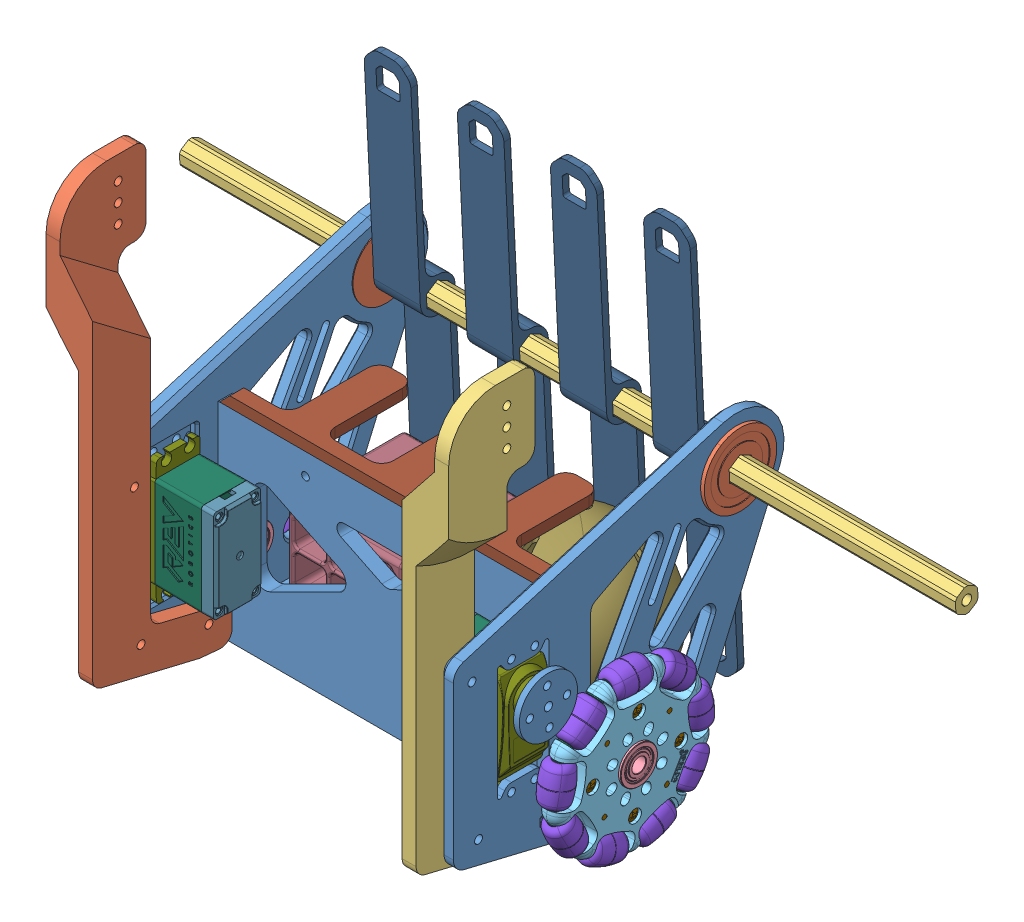
SolidWorks assembly Intake2, configuration Default. Lengths in mm.
Overall size (333.38 212.44 158.53).
109 component instances, 21 part files, 66 mates.
Components (placement in the parent):
- IntakeWide-1: IntakeWide [Default] at (-43.2378 29.5162 123.384) size (157 122.29 142.09)
- 0_375_Hex_ID_x_1_125_OD_x_0_313_WD_Flanged_Bearing_217-2735 (1).step-1: 0_375_Hex_ID_x_1_125_OD_x_0_313_WD_Flanged_Bearing_217-2735 (1).step [Default] at (101.4122 125.5162 108.384) x (0 0.54174 -0.840546) z (0 -0.840546 -0.54174) size (31.12 7.94 31.12)
- 0_375_Hex_ID_x_1_125_OD_x_0_313_WD_Flanged_Bearing_217-2735 (1).step-2: 0_375_Hex_ID_x_1_125_OD_x_0_313_WD_Flanged_Bearing_217-2735 (1).step [Default] at (-42.8878 125.5162 108.384) x (0 0.998804 0.048888) z (0 -0.048888 0.998804) size (31.12 7.94 31.12)
- 375Hex13.3in-1: 375Hex13.3in [Default] at (-250.6814 125.5123 108.3763) x (0 0.54174 -0.840546) z (-1 0 0) size (10.24 9.53 333.38)
- 1601-0014-0006.step-1: 1601-0014-0006.step [Default] at (105.8122 50.5162 165.184) x (0 -0.381849 0.924225) z (0 -0.924225 -0.381849) size (15.95 5 15.95)
- 1601-0014-0006.step-2: 1601-0014-0006.step [Default] at (-47.2878 50.5162 165.184) x (0 -1 0) z (0 0 1) size (15.95 5 15.95)
- 3604-0014-0072 assembly.STEP-1: 3604-0014-0072 assembly.STEP [Default] at (98.0385 34.1974 194.2388) x (0 -0.339821 0.94049) z (0 0.94049 0.339821) size (78.59 16.98 77.39)
  - 3604-0014-0072 wheel half.STEP-1: 3604-0014-0072 wheel half.STEP [Default] at (-32.8712 13.6737 5.4742) size (67.84 5 66.97)
  - 3604-0014-0072 wheel half.STEP-2: 3604-0014-0072 wheel half.STEP [Default] at (-32.8712 23.6737 5.4742) x (-1 0 0) z (0 0 1) size (67.84 5 66.97)
  - 3604-0014-0072 bushing.STEP-1: 3604-0014-0072 bushing.STEP [Default] at (-52.1548 18.6737 -17.5071) x (-0.130318 0.979233 -0.155307) z (-0.766044 0 0.642788) size (5.61 5.61 17.1)
  - 3604-0014-0072 shaft.STEP-1: 3604-0014-0072 shaft.STEP [Default] at (-60.0068 18.6737 -10.9185) x (0.629069 0.205497 0.749695) z (-0.132091 0.978658 -0.15742) size (3.17 20.5 3.17)
  - 3604-0014-0072 roller.STEP-1: 3604-0014-0072 roller.STEP [Default] at (-52.1548 18.6737 -17.5071) x (-0.385664 0.800009 -0.459617) z (-0.766044 0 0.642788) size (12.13 12.13 16)
  - 3604-0014-0072 shaft.STEP-2: 3604-0014-0072 shaft.STEP [Default] at (-43.1212 18.6737 -24.5258) x (0 0.205497 0.978658) z (0 0.978658 -0.205497) size (3.17 20.5 3.17)
  - 3604-0014-0072 shaft.STEP-3: 3604-0014-0072 shaft.STEP [Default] at (-21.4395 18.6737 -24.0957) x (-0.629069 0.205497 0.749695) z (0.132091 0.978658 -0.15742) size (3.17 20.5 3.17)
  - 3604-0014-0072 shaft.STEP-4: 3604-0014-0072 shaft.STEP [Default] at (-5.1069 18.6737 -9.8295) x (-0.96379 0.205497 0.169942) z (0.202375 0.978658 -0.035684) size (3.17 20.5 3.17)
  - 3604-0014-0072 shaft.STEP-5: 3604-0014-0072 shaft.STEP [Default] at (-1.7654 18.6737 11.5975) x (-0.847543 0.205497 -0.489329) z (0.177965 0.978658 0.102748) size (3.17 20.5 3.17)
  - 3604-0014-0072 shaft.STEP-6: 3604-0014-0072 shaft.STEP [Default] at (-12.9787 18.6737 30.1593) x (-0.334721 0.205497 -0.919638) z (0.070284 0.978658 0.193104) size (3.17 20.5 3.17)
  - 3604-0014-0072 shaft.STEP-7: 3604-0014-0072 shaft.STEP [Default] at (-33.4999 18.6737 37.1707) x (0.334721 0.205497 -0.919638) z (-0.070284 0.978658 0.193104) size (3.17 20.5 3.17)
  - 3604-0014-0072 shaft.STEP-8: 3604-0014-0072 shaft.STEP [Default] at (-53.727 18.6737 29.351) x (0.847543 0.205497 -0.489329) z (-0.177965 0.978658 0.102748) size (3.17 20.5 3.17)
  - 3604-0014-0072 shaft.STEP-9: 3604-0014-0072 shaft.STEP [Default] at (-64.1953 18.6737 10.3591) x (0.96379 0.205497 0.169942) z (-0.202375 0.978658 -0.035684) size (3.17 20.5 3.17)
  - 3604-0014-0072 bushing.STEP-2: 3604-0014-0072 bushing.STEP [Default] at (-32.8712 18.6737 -24.5258) x (0 0.979233 -0.202739) z (-1 0 0) size (5.61 5.61 17.1)
  - 3604-0014-0072 bushing.STEP-3: 3604-0014-0072 bushing.STEP [Default] at (-13.5876 18.6737 -17.5071) x (0.130318 0.979233 -0.155307) z (-0.766044 0 -0.642788) size (5.61 5.61 17.1)
  - 3604-0014-0072 bushing.STEP-4: 3604-0014-0072 bushing.STEP [Default] at (-3.327 18.6737 0.2648) x (0.199659 0.979233 -0.035205) z (-0.173648 0 -0.984808) size (5.61 5.61 17.1)
  - 3604-0014-0072 bushing.STEP-5: 3604-0014-0072 bushing.STEP [Default] at (-6.8904 18.6737 20.4742) x (0.175577 0.979233 0.101369) z (0.5 0 -0.866025) size (5.61 5.61 17.1)
  - 3604-0014-0072 bushing.STEP-6: 3604-0014-0072 bushing.STEP [Default] at (-22.6106 18.6737 33.665) x (0.069341 0.979233 0.190512) z (0.939693 0 -0.34202) size (5.61 5.61 17.1)
  - 3604-0014-0072 bushing.STEP-7: 3604-0014-0072 bushing.STEP [Default] at (-43.1318 18.6737 33.665) x (-0.069341 0.979233 0.190512) z (0.939693 0 0.34202) size (5.61 5.61 17.1)
  - 3604-0014-0072 bushing.STEP-8: 3604-0014-0072 bushing.STEP [Default] at (-58.852 18.6737 20.4742) x (-0.175577 0.979233 0.101369) z (0.5 0 0.866025) size (5.61 5.61 17.1)
  - 3604-0014-0072 bushing.STEP-9: 3604-0014-0072 bushing.STEP [Default] at (-62.4154 18.6737 0.2648) x (-0.199659 0.979233 -0.035205) z (-0.173648 0 0.984808) size (5.61 5.61 17.1)
  - 3604-0014-0072 roller.STEP-2: 3604-0014-0072 roller.STEP [Default] at (-32.8712 18.6737 -24.5258) x (0 0.800009 -0.599987) z (-1 0 0) size (12.13 12.13 16)
  - 3604-0014-0072 roller.STEP-3: 3604-0014-0072 roller.STEP [Default] at (-13.5876 18.6737 -17.5071) x (0.385664 0.800009 -0.459617) z (-0.766044 0 -0.642788) size (12.13 12.13 16)
  - 3604-0014-0072 roller.STEP-4: 3604-0014-0072 roller.STEP [Default] at (-3.327 18.6737 0.2648) x (0.590872 0.800009 -0.104187) z (-0.173648 0 -0.984808) size (12.13 12.13 16)
  - 3604-0014-0072 roller.STEP-5: 3604-0014-0072 roller.STEP [Default] at (-6.8904 18.6737 20.4742) x (0.519604 0.800009 0.299994) z (0.5 0 -0.866025) size (12.13 12.13 16)
  - 3604-0014-0072 roller.STEP-6: 3604-0014-0072 roller.STEP [Default] at (-22.6106 18.6737 33.665) x (0.205208 0.800009 0.563804) z (0.939693 0 -0.34202) size (12.13 12.13 16)
  - 3604-0014-0072 roller.STEP-7: 3604-0014-0072 roller.STEP [Default] at (-43.1318 18.6737 33.665) x (-0.205208 0.800009 0.563804) z (0.939693 0 0.34202) size (12.13 12.13 16)
  - 3604-0014-0072 roller.STEP-8: 3604-0014-0072 roller.STEP [Default] at (-58.852 18.6737 20.4742) x (-0.519604 0.800009 0.299994) z (0.5 0 0.866025) size (12.13 12.13 16)
  - 3604-0014-0072 roller.STEP-9: 3604-0014-0072 roller.STEP [Default] at (-62.4154 18.6737 0.2648) x (-0.590872 0.800009 -0.104187) z (-0.173648 0 0.984808) size (12.13 12.13 16)
  - 364 omni wheel screw_99461A110.STEP-1: 364 omni wheel screw_99461A110.STEP [Default] at (-40.1422 17.6737 23.0279) x (1 0 0) z (0 1 0) size (5.22 5.22 9.61)
  - 364 omni wheel screw_99461A110.STEP-2: 364 omni wheel screw_99461A110.STEP [Default] at (-50.4249 17.6737 -1.7968) x (0 0 1) z (0 1 0) size (5.22 5.22 9.61)
  - 364 omni wheel screw_99461A110.STEP-3: 364 omni wheel screw_99461A110.STEP [Default] at (-25.6002 17.6737 -12.0795) x (-1 0 0) z (0 1 0) size (5.22 5.22 9.61)
  - 364 omni wheel screw_99461A110.STEP-4: 364 omni wheel screw_99461A110.STEP [Default] at (-15.3175 17.6737 12.7452) x (0 0 -1) z (0 1 0) size (5.22 5.22 9.61)
  - 364 omni wheel screw_99461A110.STEP-5: 364 omni wheel screw_99461A110.STEP [Default] at (-25.6002 19.6737 23.0279) x (-0.837169 0 -0.546944) z (0 -1 0) size (5.22 5.22 9.61)
  - 364 omni wheel screw_99461A110.STEP-6: 364 omni wheel screw_99461A110.STEP [Default] at (-15.3175 19.6737 -1.7968) x (-0.546944 0 0.837169) z (0 -1 0) size (5.22 5.22 9.61)
  - 364 omni wheel screw_99461A110.STEP-7: 364 omni wheel screw_99461A110.STEP [Default] at (-40.1422 19.6737 -12.0795) x (0.837169 0 0.546944) z (0 -1 0) size (5.22 5.22 9.61)
  - 364 omni wheel screw_99461A110.STEP-8: 364 omni wheel screw_99461A110.STEP [Default] at (-50.4249 19.6737 12.7452) x (0.546944 0 -0.837169) z (0 -1 0) size (5.22 5.22 9.61)
- 1601-0014-0006.step-5: 1601-0014-0006.step [Default] at (117.6622 50.5162 165.184) x (0 0.825172 0.564882) z (0 0.564882 -0.825172) size (15.95 5 15.95)
- 1601-0014-0006.step-6: 1601-0014-0006.step [Default] at (115.7622 50.5162 165.184) x (0 -0.381849 0.924225) z (0 -0.924225 -0.381849) size (15.95 5 15.95)
- 1601-0014-0006.step-7: 1601-0014-0006.step [Default] at (-58.1878 50.5162 165.184) x (0 -0.381849 0.924225) z (0 -0.924225 -0.381849) size (15.95 5 15.95)
- 1601-0014-0006.step-8: 1601-0014-0006.step [Default] at (-56.2878 50.5162 165.184) x (0 0.825172 0.564882) z (0 0.564882 -0.825172) size (15.95 5 15.95)
- 3604-0014-0072 assembly.STEP-2: 3604-0014-0072 assembly.STEP [Default] at (-75.9115 34.6322 194.4787) x (0 -0.32577 0.945449) z (0 0.945449 0.32577) size (78.59 16.98 77.39)
  - 3604-0014-0072 wheel half.STEP-1: 3604-0014-0072 wheel half.STEP [Default] at (-32.8712 13.6737 5.4742) size (67.84 5 66.97)
  - 3604-0014-0072 wheel half.STEP-2: 3604-0014-0072 wheel half.STEP [Default] at (-32.8712 23.6737 5.4742) x (-1 0 0) z (0 0 1) size (67.84 5 66.97)
  - 3604-0014-0072 bushing.STEP-1: 3604-0014-0072 bushing.STEP [Default] at (-52.1548 18.6737 -17.5071) x (-0.130318 0.979233 -0.155307) z (-0.766044 0 0.642788) size (5.61 5.61 17.1)
  - 3604-0014-0072 shaft.STEP-1: 3604-0014-0072 shaft.STEP [Default] at (-60.0068 18.6737 -10.9185) x (0.629069 0.205497 0.749695) z (-0.132091 0.978658 -0.15742) size (3.17 20.5 3.17)
  - 3604-0014-0072 roller.STEP-1: 3604-0014-0072 roller.STEP [Default] at (-52.1548 18.6737 -17.5071) x (-0.385664 0.800009 -0.459617) z (-0.766044 0 0.642788) size (12.13 12.13 16)
  - 3604-0014-0072 shaft.STEP-2: 3604-0014-0072 shaft.STEP [Default] at (-43.1212 18.6737 -24.5258) x (0 0.205497 0.978658) z (0 0.978658 -0.205497) size (3.17 20.5 3.17)
  - 3604-0014-0072 shaft.STEP-3: 3604-0014-0072 shaft.STEP [Default] at (-21.4395 18.6737 -24.0957) x (-0.629069 0.205497 0.749695) z (0.132091 0.978658 -0.15742) size (3.17 20.5 3.17)
  - 3604-0014-0072 shaft.STEP-4: 3604-0014-0072 shaft.STEP [Default] at (-5.1069 18.6737 -9.8295) x (-0.96379 0.205497 0.169942) z (0.202375 0.978658 -0.035684) size (3.17 20.5 3.17)
  - 3604-0014-0072 shaft.STEP-5: 3604-0014-0072 shaft.STEP [Default] at (-1.7654 18.6737 11.5975) x (-0.847543 0.205497 -0.489329) z (0.177965 0.978658 0.102748) size (3.17 20.5 3.17)
  - 3604-0014-0072 shaft.STEP-6: 3604-0014-0072 shaft.STEP [Default] at (-12.9787 18.6737 30.1593) x (-0.334721 0.205497 -0.919638) z (0.070284 0.978658 0.193104) size (3.17 20.5 3.17)
  - 3604-0014-0072 shaft.STEP-7: 3604-0014-0072 shaft.STEP [Default] at (-33.4999 18.6737 37.1707) x (0.334721 0.205497 -0.919638) z (-0.070284 0.978658 0.193104) size (3.17 20.5 3.17)
  - 3604-0014-0072 shaft.STEP-8: 3604-0014-0072 shaft.STEP [Default] at (-53.727 18.6737 29.351) x (0.847543 0.205497 -0.489329) z (-0.177965 0.978658 0.102748) size (3.17 20.5 3.17)
  - 3604-0014-0072 shaft.STEP-9: 3604-0014-0072 shaft.STEP [Default] at (-64.1953 18.6737 10.3591) x (0.96379 0.205497 0.169942) z (-0.202375 0.978658 -0.035684) size (3.17 20.5 3.17)
  - 3604-0014-0072 bushing.STEP-2: 3604-0014-0072 bushing.STEP [Default] at (-32.8712 18.6737 -24.5258) x (0 0.979233 -0.202739) z (-1 0 0) size (5.61 5.61 17.1)
  - 3604-0014-0072 bushing.STEP-3: 3604-0014-0072 bushing.STEP [Default] at (-13.5876 18.6737 -17.5071) x (0.130318 0.979233 -0.155307) z (-0.766044 0 -0.642788) size (5.61 5.61 17.1)
  - 3604-0014-0072 bushing.STEP-4: 3604-0014-0072 bushing.STEP [Default] at (-3.327 18.6737 0.2648) x (0.199659 0.979233 -0.035205) z (-0.173648 0 -0.984808) size (5.61 5.61 17.1)
  - 3604-0014-0072 bushing.STEP-5: 3604-0014-0072 bushing.STEP [Default] at (-6.8904 18.6737 20.4742) x (0.175577 0.979233 0.101369) z (0.5 0 -0.866025) size (5.61 5.61 17.1)
  - 3604-0014-0072 bushing.STEP-6: 3604-0014-0072 bushing.STEP [Default] at (-22.6106 18.6737 33.665) x (0.069341 0.979233 0.190512) z (0.939693 0 -0.34202) size (5.61 5.61 17.1)
  - 3604-0014-0072 bushing.STEP-7: 3604-0014-0072 bushing.STEP [Default] at (-43.1318 18.6737 33.665) x (-0.069341 0.979233 0.190512) z (0.939693 0 0.34202) size (5.61 5.61 17.1)
  - 3604-0014-0072 bushing.STEP-8: 3604-0014-0072 bushing.STEP [Default] at (-58.852 18.6737 20.4742) x (-0.175577 0.979233 0.101369) z (0.5 0 0.866025) size (5.61 5.61 17.1)
  - 3604-0014-0072 bushing.STEP-9: 3604-0014-0072 bushing.STEP [Default] at (-62.4154 18.6737 0.2648) x (-0.199659 0.979233 -0.035205) z (-0.173648 0 0.984808) size (5.61 5.61 17.1)
  - 3604-0014-0072 roller.STEP-2: 3604-0014-0072 roller.STEP [Default] at (-32.8712 18.6737 -24.5258) x (0 0.800009 -0.599987) z (-1 0 0) size (12.13 12.13 16)
  - 3604-0014-0072 roller.STEP-3: 3604-0014-0072 roller.STEP [Default] at (-13.5876 18.6737 -17.5071) x (0.385664 0.800009 -0.459617) z (-0.766044 0 -0.642788) size (12.13 12.13 16)
  - 3604-0014-0072 roller.STEP-4: 3604-0014-0072 roller.STEP [Default] at (-3.327 18.6737 0.2648) x (0.590872 0.800009 -0.104187) z (-0.173648 0 -0.984808) size (12.13 12.13 16)
  - 3604-0014-0072 roller.STEP-5: 3604-0014-0072 roller.STEP [Default] at (-6.8904 18.6737 20.4742) x (0.519604 0.800009 0.299994) z (0.5 0 -0.866025) size (12.13 12.13 16)
  - 3604-0014-0072 roller.STEP-6: 3604-0014-0072 roller.STEP [Default] at (-22.6106 18.6737 33.665) x (0.205208 0.800009 0.563804) z (0.939693 0 -0.34202) size (12.13 12.13 16)
  - 3604-0014-0072 roller.STEP-7: 3604-0014-0072 roller.STEP [Default] at (-43.1318 18.6737 33.665) x (-0.205208 0.800009 0.563804) z (0.939693 0 0.34202) size (12.13 12.13 16)
  - 3604-0014-0072 roller.STEP-8: 3604-0014-0072 roller.STEP [Default] at (-58.852 18.6737 20.4742) x (-0.519604 0.800009 0.299994) z (0.5 0 0.866025) size (12.13 12.13 16)
  - 3604-0014-0072 roller.STEP-9: 3604-0014-0072 roller.STEP [Default] at (-62.4154 18.6737 0.2648) x (-0.590872 0.800009 -0.104187) z (-0.173648 0 0.984808) size (12.13 12.13 16)
  - 364 omni wheel screw_99461A110.STEP-1: 364 omni wheel screw_99461A110.STEP [Default] at (-40.1422 17.6737 23.0279) x (1 0 0) z (0 1 0) size (5.22 5.22 9.61)
  - 364 omni wheel screw_99461A110.STEP-2: 364 omni wheel screw_99461A110.STEP [Default] at (-50.4249 17.6737 -1.7968) x (0 0 1) z (0 1 0) size (5.22 5.22 9.61)
  - 364 omni wheel screw_99461A110.STEP-3: 364 omni wheel screw_99461A110.STEP [Default] at (-25.6002 17.6737 -12.0795) x (-1 0 0) z (0 1 0) size (5.22 5.22 9.61)
  - 364 omni wheel screw_99461A110.STEP-4: 364 omni wheel screw_99461A110.STEP [Default] at (-15.3175 17.6737 12.7452) x (0 0 -1) z (0 1 0) size (5.22 5.22 9.61)
  - 364 omni wheel screw_99461A110.STEP-5: 364 omni wheel screw_99461A110.STEP [Default] at (-25.6002 19.6737 23.0279) x (-0.837169 0 -0.546944) z (0 -1 0) size (5.22 5.22 9.61)
  - 364 omni wheel screw_99461A110.STEP-6: 364 omni wheel screw_99461A110.STEP [Default] at (-15.3175 19.6737 -1.7968) x (-0.546944 0 0.837169) z (0 -1 0) size (5.22 5.22 9.61)
  - 364 omni wheel screw_99461A110.STEP-7: 364 omni wheel screw_99461A110.STEP [Default] at (-40.1422 19.6737 -12.0795) x (0.837169 0 0.546944) z (0 -1 0) size (5.22 5.22 9.61)
  - 364 omni wheel screw_99461A110.STEP-8: 364 omni wheel screw_99461A110.STEP [Default] at (-50.4249 19.6737 12.7452) x (0.546944 0 -0.837169) z (0 -1 0) size (5.22 5.22 9.61)
- IntakeFlap-1: IntakeFlap [Default] at (99.2622 125.5123 108.3763) x (0 -0.998804 -0.048888) z (-1 0 0) size (180 15 20)
- IntakeFlap-2: IntakeFlap [Default] at (59.2622 125.5123 108.3763) x (0 -0.998804 -0.048888) z (-1 0 0) size (180 15 20)
- IntakeFlap-3: IntakeFlap [Default] at (19.2622 125.5123 108.3763) x (0 -0.998804 -0.048888) z (-1 0 0) size (180 15 20)
- IntakeFlap-4: IntakeFlap [Default] at (-20.7378 125.5123 108.3763) x (0 -0.998804 -0.048888) z (-1 0 0) size (180 15 20)
- Part10^Intake2-1: Part10^Intake2 [Default] at (-43.2378 110.5162 123.384) x (1 0 0) z (0 1 0) size (144 45 18.5) (virtual)
- am-2850 wiffle base Ball.step-1: am-2850 wiffle base Ball.step [Default] at (66.2022 65.0762 138.624) x (0.76558 0.27445 0.581863) z (-0.623857 0.095806 0.775644) size (71.12 71.12 71.12)
- ftc-2013 2in Cube.step-1: ftc-2013 2in Cube.step [Default] at (2.2547 54.9162 145.784) size (50.8 50.8 50.94)
- REV-41-1097.STEP-1: REV-41-1097.STEP [Default] at (-13.8878 77.7662 200.1841) x (0 0 1) z (1 0 0) size (24.05 54 43.73)
  - A.STEP-1: A.STEP [Default] at origin size (20.15 40.13 8.54)
  - E.STEP-1: E.STEP [Default] at origin size (20.15 40.15 20.1)
  - C.STEP-1: C.STEP [Default] at origin size (24.05 54 13.28)
  - B.STEP-1: B.STEP [Default] at origin size (9 9 4.4)
  - D.STEP-1: D.STEP [Default] at (0 -10.0526 -30.1) x (-1 0 0) z (0 0 1) size (17.21 17.2 14.7)
- REV-41-1097.STEP-2: REV-41-1097.STEP [Default] at (72.4122 77.7662 200.1835) x (0 0 -1) z (-1 0 0) size (24.05 54 43.73)
  - A.STEP-1: A.STEP [Default] at origin size (20.15 40.13 8.54)
  - E.STEP-1: E.STEP [Default] at origin size (20.15 40.15 20.1)
  - C.STEP-1: C.STEP [Default] at origin size (24.05 54 13.28)
  - B.STEP-1: B.STEP [Default] at origin size (9 9 4.4)
  - D.STEP-1: D.STEP [Default] at (0 -10.0526 -30.1) x (-1 0 0) z (0 0 1) size (17.21 17.2 14.7)
- IntakeServoHorn-1: IntakeServoHorn [Default] at (-55.5878 87.8188 200.1841) x (0 0.715777 -0.698329) z (0 0.698329 0.715777) size (25 6 25)
- IntakeServoHorn-2: IntakeServoHorn [Default] at (114.1122 87.8188 200.1835) x (0 0.059406 -0.998234) z (0 -0.998234 -0.059406) size (25 6 25)
- Part2^Intake2-1: Part2^Intake2 [Default] at (-43.2378 29.5162 123.384) x (0 0 -1) z (1 0 0) size (60 191.86 20) (virtual)
- IntakeArm2Mir-1: IntakeArm2Mir [Default] at (89.7622 29.5162 123.384) x (0 0 -1) z (1 0 0) size (60 191.86 20)
Mates (geometry in assembly coordinates):
- Concentric1: concentric: cylinder of IntakeWide-1 through (101.7622 125.5162 108.384) axis (1 0 0) radius 14.2875; cylinder of 0_375_Hex_ID_x_1_125_OD_x_0_313_WD_Flanged_Bearing_217-2735 (1).step-1 through (101.4122 125.5162 108.384) axis (1 0 0) radius 14.2748
- Coincident1: coincident: plane of IntakeWide-1 through (107.7622 23.5162 174.184) normal (1 0 0); plane of 0_375_Hex_ID_x_1_125_OD_x_0_313_WD_Flanged_Bearing_217-2735 (1).step-1 through (107.7622 133.9444 95.3072) normal (-1 0 0)
- Concentric2: concentric: cylinder of IntakeWide-1 through (-43.2378 125.5162 108.384) axis (-1 0 0) radius 14.2875; cylinder of 0_375_Hex_ID_x_1_125_OD_x_0_313_WD_Flanged_Bearing_217-2735 (1).step-2 through (-42.8878 125.5162 108.384) axis (-1 0 0) radius 14.2748
- Coincident2: coincident: plane of IntakeWide-1 through (-49.2378 23.5162 174.184) normal (-1 0 0); plane of 0_375_Hex_ID_x_1_125_OD_x_0_313_WD_Flanged_Bearing_217-2735 (1).step-2 through (-49.2378 141.0551 109.1446) normal (1 0 0)
- Coincident3: coincident: plane of 0_375_Hex_ID_x_1_125_OD_x_0_313_WD_Flanged_Bearing_217-2735 (1).step-1 through (127.3102 122.9988 103.4851) normal (0 0.840546 0.54174); plane of 375Hex13.3in-1 through (-707.8814 122.9988 103.4851) normal (0 -0.840546 -0.54174)
- Coincident4: coincident: plane of 0_375_Hex_ID_x_1_125_OD_x_0_313_WD_Flanged_Bearing_217-2735 (1).step-2 through (-68.7858 120.0149 108.1147) normal (0 0.840546 0.54174); plane of 375Hex13.3in-1 through (-707.8814 122.9988 103.4851) normal (0 -0.840546 -0.54174)
- Coincident5: coincident: plane of 0_375_Hex_ID_x_1_125_OD_x_0_313_WD_Flanged_Bearing_217-2735 (1).step-1 through (127.3102 128.5001 103.7544) normal (0 -0.048888 0.998804); plane of 375Hex13.3in-1 through (-707.8814 128.4914 103.7539) normal (0 0.048888 -0.998804)
- Concentric3: concentric: cylinder of IntakeWide-1 through (-49.2378 50.5162 165.184) axis (1 0 0) radius 7.05; cylinder of 1601-0014-0006.step-1 through (101.7622 50.5162 165.184) axis (1 0 0) radius 7
- Coincident6: coincident: plane of IntakeWide-1 through (101.7622 29.5162 174.184) normal (-1 0 0); plane of 1601-0014-0006.step-1 through (101.7622 50.5162 165.184) normal (1 0 0)
- Coincident7: coincident: plane of IntakeWide-1 through (-43.2378 29.5162 174.184) normal (1 0 0); plane of 1601-0014-0006.step-2 through (-43.2378 50.5162 165.184) normal (-1 0 0)
- Concentric4: concentric: cylinder of IntakeWide-1 through (-49.2378 50.5162 165.184) axis (1 0 0) radius 7.05; cylinder of 1601-0014-0006.step-2 through (-43.2378 50.5162 165.184) axis (-1 0 0) radius 7
- Coincident8: coincident: circle of 3604-0014-0072 assembly.STEP-1/3604-0014-0072 wheel half.STEP-2; cylinder of 1601-0014-0006.step-5 through (121.7122 50.5162 165.184) axis (-1 0 0) radius 7
- Coincident9: coincident: plane of 3604-0014-0072 assembly.STEP-1/3604-0014-0072 wheel half.STEP-2 through (121.7122 50.5162 165.184) normal (1 0 0); plane of 1601-0014-0006.step-5 through (121.7122 50.5162 165.184) normal (-1 0 0)
- Concentric5: concentric: cylinder of 3604-0014-0072 assembly.STEP-1/3604-0014-0072 wheel half.STEP-1 through (111.7122 50.5162 165.184) axis (1 0 0) radius 7; cylinder of 1601-0014-0006.step-6 through (111.7122 50.5162 165.184) axis (1 0 0) radius 7
- Coincident10: coincident: plane of 3604-0014-0072 assembly.STEP-1/3604-0014-0072 wheel half.STEP-1 through (111.7122 50.5162 165.184) normal (-1 0 0); plane of 1601-0014-0006.step-6 through (111.7122 50.5162 165.184) normal (1 0 0)
- Concentric6: concentric: cylinder of 1601-0014-0006.step-1 through (105.8122 50.5162 165.184) axis (-1 0 0) radius 3; cylinder of 1601-0014-0006.step-5 through (117.6622 50.5162 165.184) axis (1 0 0) radius 3
- Distance2: distance = 3 mm: plane of 1601-0014-0006.step-6 through (110.7622 50.5162 165.184) normal (-1 0 0); plane of IntakeWide-1 through (107.7622 23.5162 174.184) normal (1 0 0)
- Concentric7: concentric: cylinder of 1601-0014-0006.step-7 through (-62.2378 50.5162 165.184) axis (1 0 0) radius 7; cylinder of 3604-0014-0072 assembly.STEP-2/3604-0014-0072 wheel half.STEP-1 through (-62.2378 50.5162 165.184) axis (1 0 0) radius 7
- Coincident13: coincident: cylinder of 1601-0014-0006.step-8 through (-52.2378 50.5162 165.184) axis (-1 0 0) radius 7; circle of 3604-0014-0072 assembly.STEP-2/3604-0014-0072 wheel half.STEP-2
- Coincident14: coincident: plane of 1601-0014-0006.step-8 through (-52.2378 50.5162 165.184) normal (-1 0 0); plane of 3604-0014-0072 assembly.STEP-2/3604-0014-0072 wheel half.STEP-2 through (-52.2378 50.5162 165.184) normal (1 0 0)
- Coincident15: coincident: plane of 1601-0014-0006.step-7 through (-62.2378 50.5162 165.184) normal (1 0 0); plane of 3604-0014-0072 assembly.STEP-2/3604-0014-0072 wheel half.STEP-1 through (-62.2378 50.5162 165.184) normal (-1 0 0)
- Concentric8: concentric: cylinder of 1601-0014-0006.step-2 through (-47.2878 50.5162 165.184) axis (1 0 0) radius 3; cylinder of 1601-0014-0006.step-7 through (-58.1878 50.5162 165.184) axis (-1 0 0) radius 3
- Distance3: distance = 3 mm: plane of 3604-0014-0072 assembly.STEP-2/3604-0014-0072 wheel half.STEP-2 through (-52.2378 50.5162 165.184) normal (1 0 0); plane of IntakeWide-1 through (-49.2378 23.5162 174.184) normal (-1 0 0)
- Coincident17: coincident: plane of 375Hex13.3in-1 through (-707.8814 128.4914 103.7539) normal (0 0.048888 -0.998804); plane of IntakeFlap-1 through (79.2622 128.4914 103.7539) normal (0 -0.048888 0.998804)
- Coincident18: coincident: plane of 375Hex13.3in-1 through (-707.8814 122.9988 103.4851) normal (0 -0.840546 -0.54174); plane of IntakeFlap-1 through (79.2622 122.9988 103.4851) normal (0 0.840546 0.54174)
- Coincident19: coincident: plane of 375Hex13.3in-1 through (-707.8814 122.5331 112.9987) normal (0 -0.048888 0.998804); plane of IntakeFlap-2 through (39.2622 122.5331 112.9987) normal (0 0.048888 -0.998804)
- Coincident20: coincident: plane of 375Hex13.3in-1 through (-707.8814 122.5331 112.9987) normal (0 -0.048888 0.998804); plane of IntakeFlap-3 through (-0.7378 122.5331 112.9987) normal (0 0.048888 -0.998804)
- Coincident21: coincident: plane of 375Hex13.3in-1 through (-707.8814 122.5331 112.9987) normal (0 -0.048888 0.998804); plane of IntakeFlap-4 through (-40.7378 122.5331 112.9987) normal (0 0.048888 -0.998804)
- Coincident22: coincident: plane of 375Hex13.3in-1 through (-707.8814 128.0258 113.2675) normal (0 0.840546 0.54174); plane of IntakeFlap-2 through (39.2622 128.0258 113.2675) normal (0 -0.840546 -0.54174)
- Coincident23: coincident: plane of 375Hex13.3in-1 through (-707.8814 128.0258 113.2675) normal (0 0.840546 0.54174); plane of IntakeFlap-3 through (-0.7378 128.0258 113.2675) normal (0 -0.840546 -0.54174)
- Coincident24: coincident: plane of 375Hex13.3in-1 through (-707.8814 122.9988 103.4851) normal (0 -0.840546 -0.54174); plane of IntakeFlap-4 through (-40.7378 122.9988 103.4851) normal (0 0.840546 0.54174)
- Distance4: distance = 20 mm: plane of IntakeFlap-2 through (59.2622 125.5123 108.3763) normal (1 0 0); plane of IntakeFlap-1 through (79.2622 125.5123 108.3763) normal (-1 0 0)
- Distance5: distance = 20 mm: plane of IntakeFlap-2 through (39.2622 125.5123 108.3763) normal (-1 0 0); plane of IntakeFlap-3 through (19.2622 125.5123 108.3763) normal (1 0 0)
- Distance6: distance = 20 mm: plane of IntakeFlap-4 through (-20.7378 125.5123 108.3763) normal (1 0 0); plane of IntakeFlap-3 through (-0.7378 125.5123 108.3763) normal (-1 0 0)
- Distance7: distance = 2.5 mm: plane of IntakeWide-1 through (101.7622 29.5162 174.184) normal (-1 0 0); plane of IntakeFlap-1 through (99.2622 125.5123 108.3763) normal (1 0 0)
- InPlace1: in place: plane of IntakeWide-1 through (-49.2378 110.5162 174.184) normal (0 1 0); plane of ? through (0 110.5162 0) normal (0 1 0); moOrthogonalPlaneRef_w of IntakeWide-1 through (-49.2378 110.5162 174.184) normal (0 1 0); plane of ? through (0 110.5162 0) normal (0 0 -1); plane of IntakeWide-1 through (-49.2378 110.5162 174.184) normal (0 1 0); plane of ? through (0 110.5162 0) normal (1 0 0); plane of IntakeWide-1 through (-49.2378 110.5162 174.184) normal (0 1 0); unknown of Part10^Intake2-1
- Coincident29: coincident: plane of IntakeWide-1; plane of Part10^Intake2-1
- Coincident30: coincident: moOrthogonalPlaneRef_w of IntakeWide-1 through (-43.2378 110.5162 123.384) normal (0 0 -1); plane of Part10^Intake2-1 through (-43.2378 110.5162 123.384) normal (0 0 -1)
- Coincident31: coincident: moOrthogonalPlaneRef_w of IntakeWide-1 through (-43.2378 110.5162 123.384) normal (-1 0 0); plane of Part10^Intake2-1 through (-43.2378 110.5162 123.384) normal (1 0 0)
- Tangent1: tangent: plane of IntakeWide-1 through (-43.2378 29.5162 174.184) normal (0 1 0); sphere of am-2850 wiffle base Ball.step-1
- Tangent2: tangent: plane of IntakeWide-1 through (-43.2378 29.5162 174.184) normal (0 0 -1); sphere of am-2850 wiffle base Ball.step-1
- Tangent3: tangent: plane of IntakeWide-1 through (101.7622 29.5162 174.184) normal (-1 0 0); sphere of am-2850 wiffle base Ball.step-1
- Coincident32: coincident: plane of IntakeWide-1 through (-43.2378 29.5162 174.184) normal (0 1 0); plane of ftc-2013 2in Cube.step-1 through (27.6547 29.5162 120.384) normal (0 -1 0)
- Distance8: distance = 3 mm: plane of ftc-2013 2in Cube.step-1 through (-23.1453 80.3162 171.184) normal (0 0 1); plane of IntakeWide-1 through (-43.2378 29.5162 174.184) normal (0 0 -1)
- Coincident33: coincident: plane of IntakeWide-1 through (-43.2378 29.5162 174.184) normal (1 0 0); plane of REV-41-1097.STEP-1/C.STEP-1 through (-43.2378 77.7662 200.1841) normal (-1 0 0)
- Concentric9: concentric: cylinder of IntakeWide-1 through (-43.2378 102.5162 205.1841) axis (-1 0 0) radius 1.65; cylinder of ? through (-43.2378 102.5162 205.1841) axis (-1 0 0) radius 2.25
- Concentric10: concentric: cylinder of IntakeWide-1 through (-43.2378 102.5162 195.1835) axis (-1 0 0) radius 1.65; cylinder of ? through (-43.2378 102.5162 195.1841) axis (-1 0 0) radius 2.25
- Concentric11: concentric: circle of IntakeWide-1; cylinder of ? through (101.7622 102.5162 195.1835) axis (1 0 0) radius 2.25
- Concentric12: concentric: circle of IntakeWide-1; cylinder of ? through (101.7622 102.5162 205.1835) axis (1 0 0) radius 2.25
- Coincident34: coincident: plane of IntakeWide-1 through (101.7622 29.5162 174.184) normal (-1 0 0); plane of ? through (101.7622 77.7662 200.1835) normal (1 0 0)
- Concentric13: concentric: circle of REV-41-1097.STEP-1/D.STEP-1; cylinder of IntakeServoHorn-1 through (-60.0878 87.8188 200.1841) axis (1 0 0) radius 1.75
- Coincident35: coincident: plane of REV-41-1097.STEP-1/D.STEP-1 through (-57.5878 87.8188 200.1841) normal (-1 0 0); plane of IntakeServoHorn-1 through (-57.5878 87.8188 200.1841) normal (1 0 0)
- Concentric14: concentric: circle of REV-41-1097.STEP-2/D.STEP-1; cylinder of IntakeServoHorn-2 through (116.1122 87.8188 200.1835) axis (1 0 0) radius 12.5
- Coincident36: coincident: plane of REV-41-1097.STEP-2/D.STEP-1 through (116.1122 87.8188 200.1835) normal (1 0 0); plane of IntakeServoHorn-2 through (116.1122 87.8188 200.1835) normal (-1 0 0)
- BeltMate1: belt = 4.2 : 25 mm: circle of IntakeServoHorn-1; cylinder of 375Hex13.3in-1 through (206.5186 125.5123 108.3763) axis (-1 0 0) radius 2.1
- InPlace2: in place: plane of IntakeWide-1 through (-43.2378 29.5162 174.184) normal (1 0 0); plane of ? through (-43.2378 0 0) normal (1 0 0); plane of IntakeWide-1 through (-43.2378 29.5162 174.184) normal (1 0 0); plane of ? through (-43.2378 0 0) normal (0 1 0); plane of IntakeWide-1 through (-43.2378 29.5162 174.184) normal (1 0 0); plane of ? through (-43.2378 0 0) normal (0 0 -1); plane of IntakeWide-1 through (-43.2378 29.5162 174.184) normal (1 0 0); unknown of Part2^Intake2-1
- Coincident37: coincident: plane of IntakeWide-1; plane of ?
- Coincident38: coincident: moOrthogonalPlaneRef_w of IntakeWide-1 through (-43.2378 29.5162 123.384) normal (0 1 0); plane of Part2^Intake2-1 through (-43.2378 29.5162 123.384) normal (0 1 0)
- Coincident39: coincident: moOrthogonalPlaneRef_w of IntakeWide-1 through (-43.2378 29.5162 123.384) normal (0 0 1); plane of Part2^Intake2-1 through (-43.2378 29.5162 123.384) normal (0 0 -1)
- InPlace3: in place: plane of IntakeWide-1 through (-43.2378 29.5162 174.184) normal (1 0 0); plane of ? through (-43.2378 0 0) normal (1 0 0); plane of IntakeWide-1 through (-43.2378 29.5162 174.184) normal (1 0 0); plane of ? through (-43.2378 0 0) normal (0 1 0); plane of IntakeWide-1 through (-43.2378 29.5162 174.184) normal (1 0 0); plane of ? through (-43.2378 0 0) normal (0 0 -1); plane of IntakeWide-1 through (-43.2378 29.5162 174.184) normal (1 0 0); unknown of Part2^Intake2-1
- Coincident37: coincident: plane of IntakeWide-1; plane of Part2^Intake2-1
- Coincident38: coincident: moOrthogonalPlaneRef_w of IntakeWide-1 through (-43.2378 29.5162 123.384) normal (0 1 0); plane of Part2^Intake2-1 through (-43.2378 29.5162 123.384) normal (0 1 0)
- Coincident39: coincident: moOrthogonalPlaneRef_w of IntakeWide-1 through (-43.2378 29.5162 123.384) normal (0 0 1); plane of Part2^Intake2-1 through (-43.2378 29.5162 123.384) normal (0 0 -1)
- Concentric15: concentric: cylinder of IntakeWide-1 through (107.7622 42.5174 219.3556) axis (-1 0 0) radius 1.7; cylinder of IntakeArm2Mir-1 through (95.7622 42.5174 219.3556) axis (1 0 0) radius 1.7
- Concentric16: concentric: cylinder of IntakeWide-1 through (107.7622 102.5162 222.184) axis (-1 0 0) radius 1.7; cylinder of IntakeArm2Mir-1 through (95.7622 102.5162 222.184) axis (1 0 0) radius 1.7
- Coincident40: coincident: plane of IntakeWide-1 through (101.7622 29.5162 174.184) normal (-1 0 0); plane of IntakeArm2Mir-1 through (101.7622 29.5162 123.384) normal (1 0 0)
